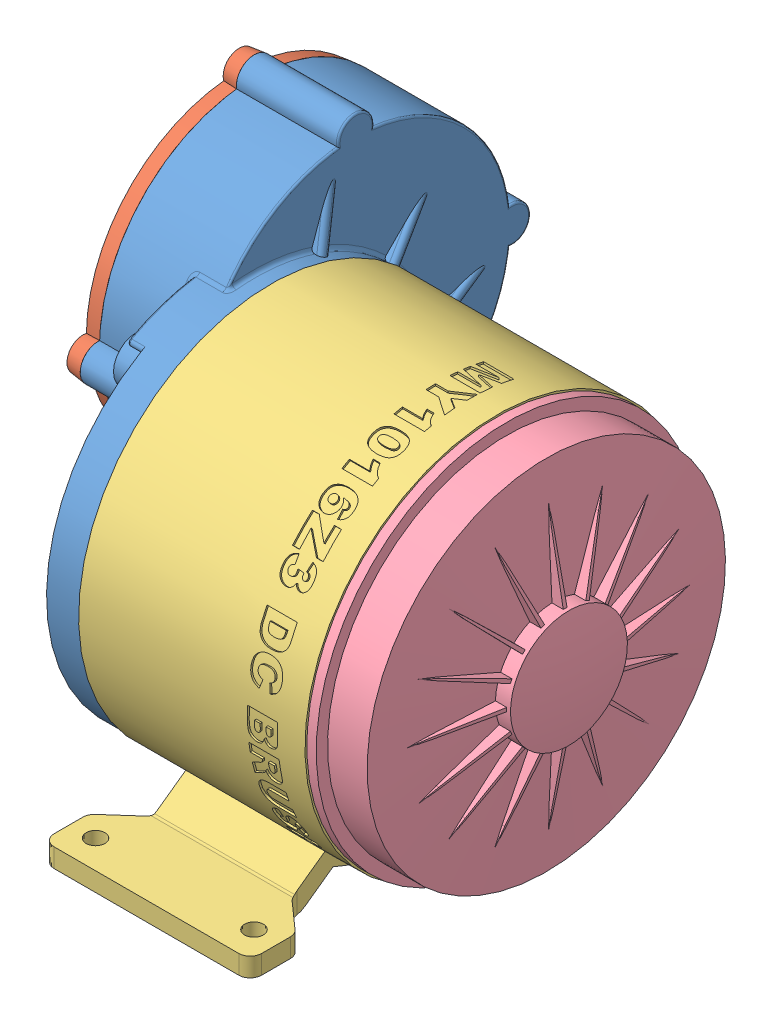
SolidWorks assembly MY1016Z3 DC MOTOR 24V 350W-2, configuration Default. Lengths in mm.
Overall size (138 204.28 184.34).
6 component instances, 5 part files, 0 mates.
Components (placement in the parent):
- MY1016Z3 DC MOTOR 24V 350W-1-1: MY1016Z3 DC MOTOR 24V 350W-1 [Default] at (-32.8716 19.5 -58.9335) x (-1 0 0) z (0 0 -1) size (138 204.28 184.34)
  - MY1016Z3 DC MOTOR 24V 350W-03-2-1: MY1016Z3 DC MOTOR 24V 350W-03-2 [Default] at (-0.8716 57 -39.4335) x (0 -0.707107 0.707107) z (1 0 0) size (101 130.5 34)
  - MY1016Z3 DC MOTOR 24V 350W-02-1: MY1016Z3 DC MOTOR 24V 350W-02 [Default] at (35.1284 84.5772 -11.8564) x (0 -0.707107 0.707107) z (1 0 0) size (82 90 7)
  - MY1016Z3 DC MOTOR 24V 350W-04-2-1: MY1016Z3 DC MOTOR 24V 350W-04-2 [Default] at (-30.8716 57 -39.4335) x (0 -0.707107 0.707107) z (1 0 0) size (130.2 130.2 65.5)
  - MY1016Z3 DC MOTOR 24V 350W-05-1: MY1016Z3 DC MOTOR 24V 350W-05 [Default] at (-60.8716 57 -39.4335) x (0 0.707107 -0.707107) z (1 0 0) size (101 101 22)
  - MY1016Z3 DC MOTOR 24V 350W-01-1: MY1016Z3 DC MOTOR 24V 350W-01 [Default] at (46.6284 84.5772 -11.8564) x (0 0 -1) z (1 0 0) size (40.71 40.13 26)
